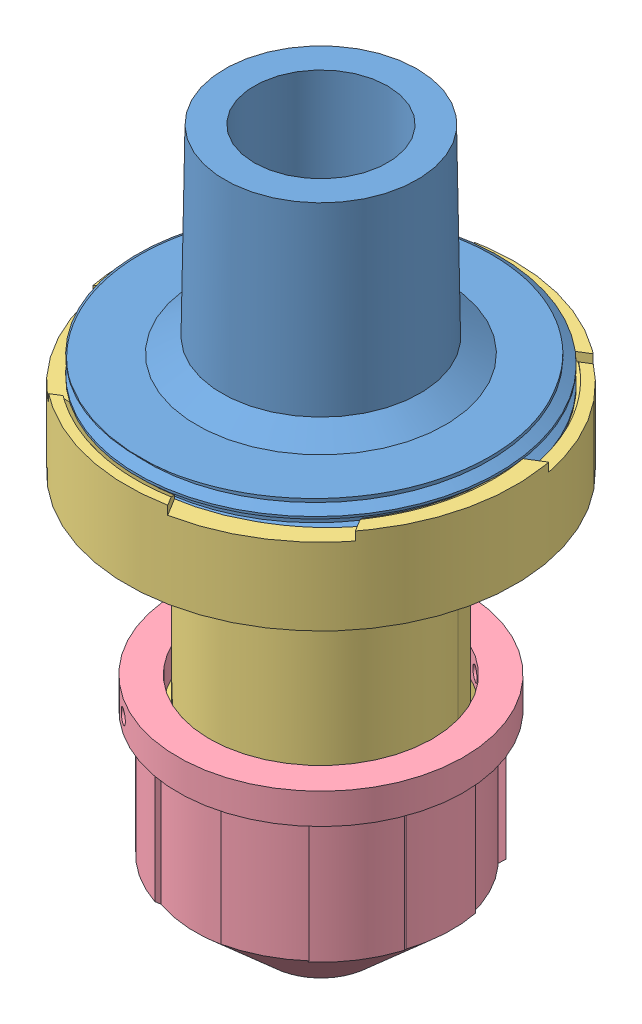
SolidWorks assembly Assy_PEEP_Valve, configuration Default. Lengths in mm.
Overall size (61.09 80.5 61.09).
8 component instances, 8 part files, 19 mates.
Components (placement in the parent):
- PEEP_Body_Non_Adjustment-1: PEEP_Body_Non_Adjustment [Default] at origin size (42.96 30.67 43.43)
- PEEP_Valve_Large_Silicone_Seal-1: PEEP_Valve_Large_Silicone_Seal [Default] at (0 28.7851 0) x (-0.776565 0 -0.630038) z (-0.630038 0 0.776565) size (35.2 9.5 35.2)
- PEEP_Body_Adjustment_Side-1: PEEP_Body_Adjustment_Side [Default] at (0 -8.7149 0) x (0.524679 0 0.8513) z (-0.8513 0 0.524679) size (44.4 38.92 44.4)
- PEEP_Adjustment_Knob-1: PEEP_Adjustment_Knob [Default] at (0 -0.5149 0) x (-0.837169 0 -0.546944) z (-0.546944 0 0.837169) size (32.7 26 32.7)
- PEEP_Pin_Center-1: PEEP_Pin_Center [Default] at (0 34.2851 0) x (-0.837169 0 -0.546944) z (-0.546944 0 0.837169) size (5.5 49 5.5)
- PEEP_Spring_Taper-1: PEEP_Spring_Taper [Default] at (0 -3.1293 0) size (13.06 27.8 13.19)
- Platic_Float-1: Platic_Float [Default] at (0 -4.9149 0) x (-0.837169 0 -0.546944) z (-0.546944 0 0.837169) size (19.4 5 19.4)
- PEEP_Spring_Large-1: PEEP_Spring_Large [Default] at (0 24.3492 0) x (0.672466 0 0.740128) z (0.740128 0 -0.672466) size (17.37 25.6 17.37)
Mates (geometry in assembly coordinates):
- Coincident1: coincident anti-aligned: plane of PEEP_Body_Non_Adjustment-1 through (-14.95 25.7851 0) normal (0 -1 0); plane of PEEP_Valve_Large_Silicone_Seal-1 through (12.891 25.7851 10.4586) normal (0 1 0)
- Concentric1: concentric anti-aligned: cylinder of PEEP_Body_Non_Adjustment-1 through (0 0 0) axis (0 -1 0) radius 14.95; cylinder of PEEP_Valve_Large_Silicone_Seal-1 through (0 28.7851 0) axis (0 1 0) radius 17.6
- Concentric2: concentric anti-aligned: circle of PEEP_Valve_Large_Silicone_Seal-1; circle of PEEP_Body_Adjustment_Side-1
- Distance1: distance = 2 mm aligned: plane of PEEP_Body_Adjustment_Side-1 through (-11.6479 29.2851 -18.8989) normal (0 1 0); plane of PEEP_Body_Non_Adjustment-1 through (-20.65 31.2851 0) normal (0 1 0)
- Distance3: distance = 1.8 mm anti-aligned: plane of PEEP_Body_Non_Adjustment-1 through (-20.65 31.2851 0) normal (0 1 0); plane of PEEP_Adapter_Outlet-1 through (18.3 33.0851 0) normal (0 -1 0)
- Concentric4: concentric aligned: cylinder of PEEP_Body_Adjustment_Side-1 through (0 -8.7149 0) axis (0 -1 0) radius 22.2; cylinder of PEEP_Adapter_Outlet-1 through (0 20.0851 0) axis (0 -1 0) radius 11.325
- Parallel1: parallel aligned: plane of PEEP_Adapter_Outlet-1 through (0 20.0851 0) normal (0 0 1)
- Coincident3: coincident anti-aligned: plane of PEEP_Valve_Large_Silicone_Seal-1 through (2.718 24.6851 2.2051) normal (0 -1 0); plane of PEEP_Pin_Center-1 through (-1.465 24.6851 -0.9572) normal (0 1 0)
- Concentric5: concentric anti-aligned: cylinder of PEEP_Valve_Large_Silicone_Seal-1 through (0 34.6851 0) axis (0 -1 0) radius 1.5; cylinder of PEEP_Pin_Center-1 through (0 34.2851 0) axis (0 1 0) radius 2.75
- Concentric6: concentric anti-aligned: cylinder of PEEP_Pin_Center-1 through (0 34.2851 0) axis (0 1 0) radius 1.5; line of PEEP_Spring_Taper-1 through (100 0 46.8707) axis (0 0 -1)
- Tangent1: tangent aligned: plane of PEEP_Pin_Center-1 through (-2.3022 23.6851 -1.5041) normal (0 -1 0); face of PEEP_Spring_Taper-1
- Coincident4: coincident anti-aligned: plane of PEEP_Pin_Center-1 through (-1.2558 -9.9149 -0.8204) normal (0 1 0); plane of Platic_Float-1 through (-6.6974 -9.9149 -4.3756) normal (0 -1 0)
- Concentric7: concentric aligned: cylinder of PEEP_Pin_Center-1 through (0 34.2851 0) axis (0 1 0) radius 1.5; cylinder of Platic_Float-1 through (0 -4.9149 0) axis (0 1 0) radius 8.1
- Concentric8: concentric anti-aligned: cylinder of PEEP_Valve_Large_Silicone_Seal-1 through (0 28.7851 0) axis (0 1 0) radius 9.3; line of PEEP_Spring_Large-1 through (100 0 74.3492) axis (0 0 -1)
- Coincident5: coincident anti-aligned: circle of PEEP_Valve_Large_Silicone_Seal-1; plane of PEEP_Spring_Large-1 through (0 24.3492 0) normal (0 -1 0)
- Coincident6: coincident anti-aligned: plane of PEEP_Adapter_Outlet-1 through (11.325 33.7851 0) normal (0 -1 0); plane of PEEP_Adapter_Outlet_Inner_Seal-1 through (-17.5 33.7851 0) normal (0 1 0)
- Concentric9: concentric aligned: cylinder of PEEP_Adapter_Outlet-1 through (0 20.0851 0) axis (0 -1 0) radius 11.325; cylinder of PEEP_Adapter_Outlet_Inner_Seal-1 through (0 31.3851 0) axis (0 -1 0) radius 17.5
- Coincident7: coincident anti-aligned: plane of PEEP_Adapter_Outlet_Seal-1 through (-26.75 22.0851 0) normal (0 -1 0); plane of PEEP_Adapter_Outlet-1 through (29.25 22.0851 0) normal (0 1 0)
- Concentric10: concentric aligned: circle of PEEP_Adapter_Outlet-1; cylinder of PEEP_Adapter_Outlet_Seal-1 through (0 16.0851 0) axis (0 -1 0) radius 24.25
